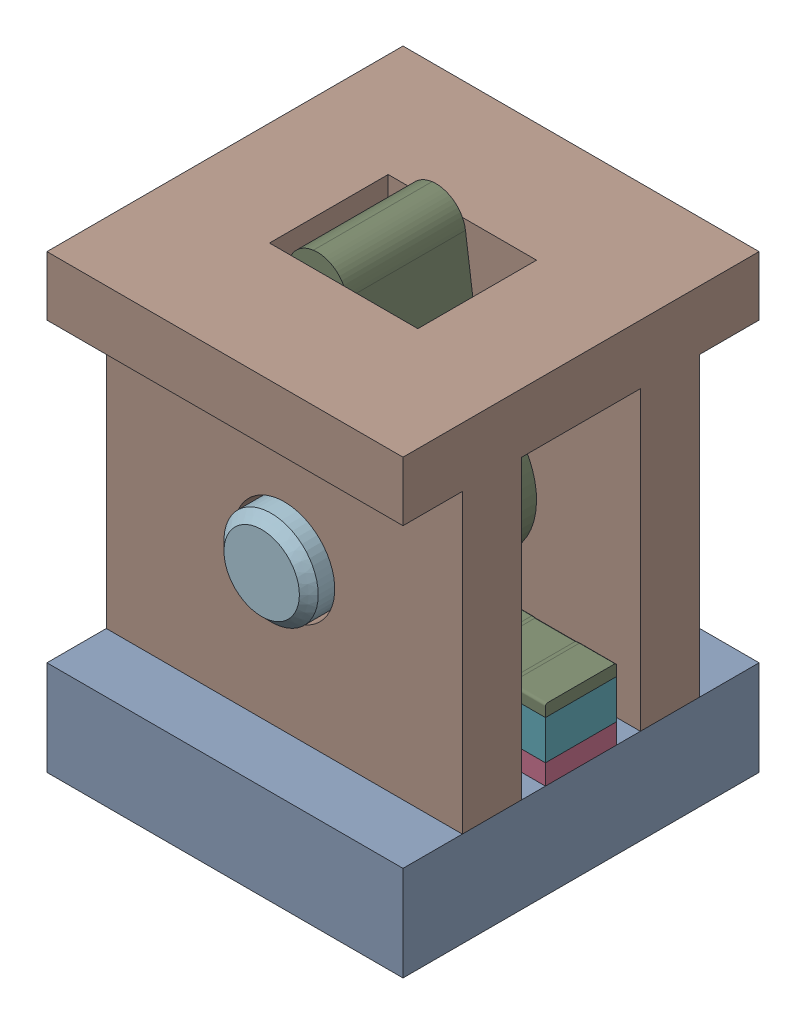
SolidWorks assembly CellAssembly, configuration Default. Lengths in mm.
Overall size (3 4.02 3).
8 component instances, 6 part files, 20 mates.
Components (placement in the parent):
- PCB-1: PCB [Default] at (-1.8095 -0.2789 1.5811) size (3 0.8 3)
- Inductor-1: Inductor [Default] at (-1.3095 0.5211 0.0811) size (1 0.6 0.6)
- Inductor-2: Inductor [Default] at (0.6905 0.5211 0.0811) size (1 0.6 0.6)
- TopSurface-1: TopSurface [Default] at (1.1905 0.5211 -1.4189) x (0 0 -1) z (1 0 0) size (3 3 3)
- Tactor-1: Tactor [Default] at (-0.0314 0.6483 -0.4189) x (0.134158 -0.99096 0) z (0 0 -1) size (3.05 1.25 1)
- Magnet-1: Magnet [Default] at (0.1668 0.6751 -0.1689) x (0.134158 -0.99096 0) z (0 0 -1) size (0.5 0.2 0.5)
- Magnet-2: Magnet [Default] at (-0.5444 1.0834 -0.1689) x (-0.134158 0.99096 0) z (0 0 -1) size (0.5 0.2 0.5)
- DowelPin-1: DowelPin [90145A106] at (-0.3095 1.7711 0.0811) x (0 0 -1) z (-1 0 0) size (2.38 0.79 0.79)
Mates (geometry in assembly coordinates):
- Coincident1: coincident anti-aligned: plane of PCB-1 through (-1.8095 0.5211 1.5811) normal (0 1 0); plane of Inductor-2 through (0.6905 0.5211 0.0811) normal (0 -1 0)
- Coincident2: coincident anti-aligned: plane of PCB-1 through (-1.8095 0.5211 1.5811) normal (0 1 0); plane of Inductor-1 through (-1.3095 0.5211 0.0811) normal (0 -1 0)
- Coincident3: coincident aligned: line of PCB-1 through (-1.8095 0.5211 -1.4189) axis (0 0 1); line of Inductor-1 through (-1.8095 0.5211 -0.2189) axis (0 0 1)
- Coincident4: coincident aligned: line of PCB-1 through (1.1905 0.5211 1.5811) axis (0 0 -1); line of Inductor-2 through (1.1905 0.5211 0.3811) axis (0 0 -1)
- Coincident5: coincident aligned: line of PCB-1 through (-1.8095 0.5211 -1.4189) axis (0 0 1); line of TopSurface-1 through (-1.8095 0.5211 0.5811) axis (0 0 1)
- Coincident6: coincident anti-aligned: plane of PCB-1 through (-1.8095 0.5211 1.5811) normal (0 1 0); plane of TopSurface-1 through (1.1905 0.5211 -1.4189) normal (0 -1 0)
- Coincident8: coincident aligned: plane of Inductor-1 through (-1.5095 2.3919 -0.2189) normal (0 0 -1); plane of Inductor-2 through (1.1905 2.3919 -0.2189) normal (0 0 -1)
- Coincident9: coincident anti-aligned: plane of Tactor-1 through (-0.2791 0.6147 -0.4189) normal (-0.99096 -0.134158 0); plane of Magnet-2 through (-0.3462 1.1102 -0.1689) normal (0.99096 0.134158 0)
- Coincident10: coincident anti-aligned: line of Tactor-1 through (-0.2791 0.6147 -0.4189) axis (0 0 1); line of Magnet-2 through (-0.2791 0.6147 0.3311) axis (0 0 -1)
- Coincident11: coincident aligned: line of Tactor-1 through (-0.3462 1.1102 0.3311) axis (0.134158 -0.99096 0); line of Magnet-2 through (-0.3462 1.1102 0.3311) axis (0.134158 -0.99096 0)
- Coincident12: coincident anti-aligned: plane of Tactor-1 through (-0.0314 0.6483 -0.4189) normal (0.99096 0.134158 0); plane of Magnet-1 through (-0.0314 0.6483 -0.1689) normal (-0.99096 -0.134158 0)
- Coincident13: coincident anti-aligned: line of Tactor-1 through (-0.0985 1.1437 0.3311) axis (0.134158 -0.99096 0); line of Magnet-1 through (-0.0314 0.6483 0.3311) axis (-0.134158 0.99096 0)
- Coincident14: coincident aligned: line of Tactor-1 through (-0.0314 0.6483 -0.4189) axis (0 0 1); line of Magnet-1 through (-0.0314 0.6483 -0.1689) axis (0 0 1)
- Concentric1: concentric anti-aligned: circle of TopSurface-1; circle of Tactor-1
- Coincident16: coincident anti-aligned: plane of TopSurface-1 through (1.1905 3.0211 -0.4189) normal (0 0 1); plane of Tactor-1 through (-0.4334 1.7543 -0.4189) normal (0 0 -1)
- Concentric2: concentric anti-aligned: circle of TopSurface-1; circle of DowelPin-1
- Coincident17: coincident aligned: line of PCB-1 through (-0.8095 0.5211 -0.4189) axis (1 0 0); line of TopSurface-1 through (-1.8095 0.5211 -0.4189) axis (1 0 0)
- Coincident18: coincident aligned: line of PCB-1 through (1.1905 0.5211 0.0811) axis (-1 0 0); line of Inductor-2 through (1.1905 0.5211 0.0811) axis (-1 0 0)
- Parallel2: parallel aligned: line of TopSurface-1 through (1.1905 0.5211 -0.9189) axis (-1 0 0); line of DowelPin-1 through (0.0873 1.7711 -0.4189) axis (-1 0 0)
- Coincident23: coincident: plane of TopSurface-1 through (1.1905 3.0211 -0.4189) normal (0 0 1); line of DowelPin-1 through (0.0873 1.7711 -0.4189) axis (-1 0 0)
